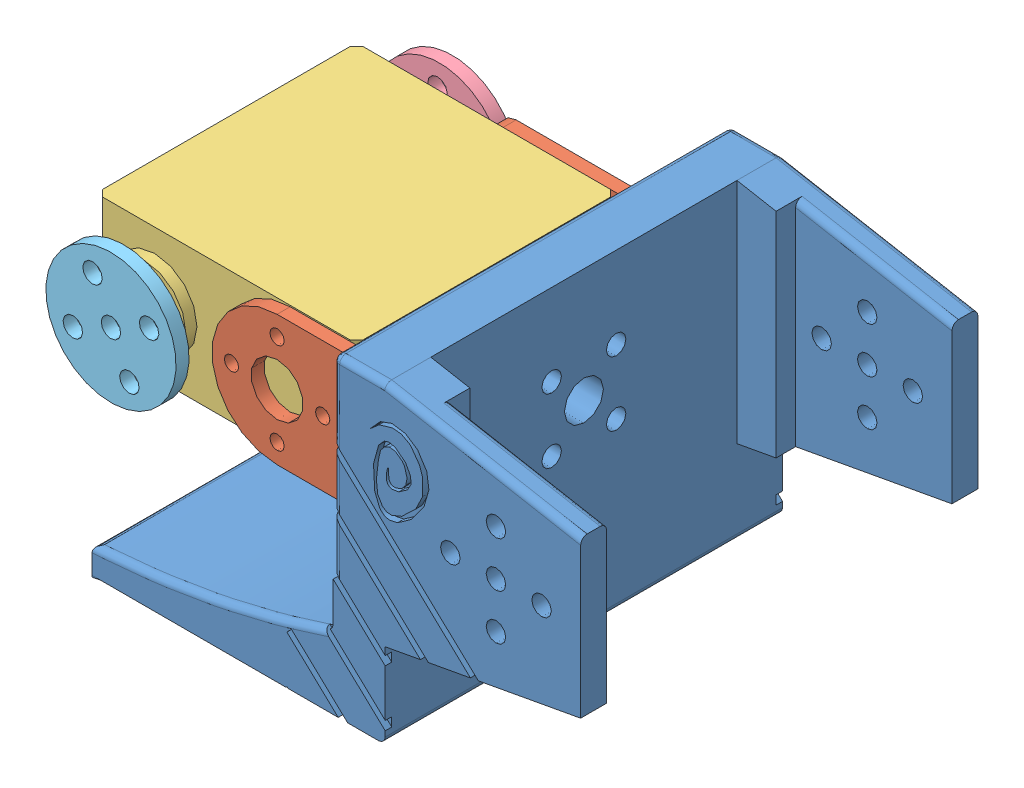
SolidWorks assembly leg2, configuration Default. Lengths in mm.
Overall size (89.36 49.5 61.19).
6 component instances, 5 part files, 3 mates.
Components (placement in the parent):
- leg1-2-1: leg1-2 [Default] at (-20.1481 19.6665 67.479) size (75 49.5 61.19)
- servo_asm-1: servo_asm [默认] at (562.42 -174.8612 347.8178) x (-1 0 0) z (0 0 -1) size (51.36 26.71 52.4)
  - ZJ-DUAN-1: ZJ-DUAN [默认] at (575.5682 225.0277 280.3388) x (-1 0 0) z (0 -1 0) size (27 44.2 20)
  - 舵机-1: 舵机 [默认] at (546.9248 215.0277 274.2891) x (-1 0 0) z (0 0 -1) size (40 20 48.7)
  - 无齿盘-1: 无齿盘 [默认] at (596.5682 225.0277 306.1388) x (-0.041997 -0.999118 0) z (0.999118 -0.041997 0) size (20 3 20)
  - 有齿盘-1: 有齿盘 [默认] at (596.5682 225.0277 253.7388) x (0.900229 -0.435417 0) z (-0.435417 -0.900229 0) size (20 4.2 20)
Mates (geometry in assembly coordinates):
- 重合1: coincident anti-aligned: plane of leg1-2-1 through (3.8519 84.6665 36.979) normal (-1 0 0); plane of servo_asm-1/ZJ-DUAN-1 through (3.8519 60.1665 45.379) normal (1 0 0)
- 同心1: concentric anti-aligned: cylinder of leg1-2-1 through (30.8519 50.1665 67.479) axis (-1 0 0) radius 3; cylinder of servo_asm-1/ZJ-DUAN-1 through (3.8519 50.1665 67.479) axis (1 0 0) radius 3
- 平行1: parallel aligned: plane of leg1-2-1 through (-20.1481 18.9165 67.479) normal (0 -1 0); plane of servo_asm-1/舵机-1 through (15.4953 40.1665 73.5287) normal (0 -1 0)
